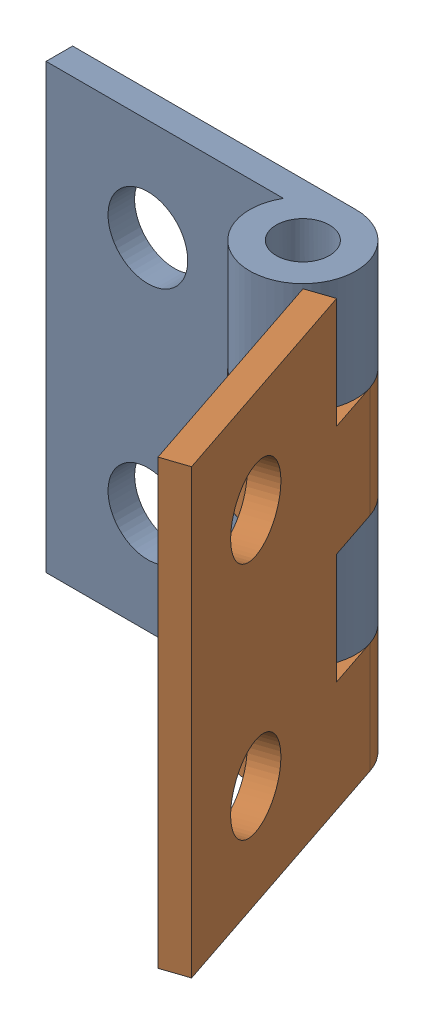
SolidWorks assembly 铰链, configuration 默认. Lengths in mm.
Overall size (23.93 25 19.92).
2 component instances, 1 part files, 2 mates.
Components (placement in the parent):
- 铰链_half-1: 铰链_half [默认] at (-3.8519 1.7615 -3) size (19 25 6)
- 铰链_half-2: 铰链_half [默认] at (11.5138 1.7615 8.0525) x (-0.318051 0 -0.948074) z (-0.948074 0 0.318051) size (19 25 6)
Mates (geometry in assembly coordinates):
- 重合1: coincident anti-aligned: plane of 铰链_half-1 through (8.6481 8.0115 3) normal (0 -1 0); plane of 铰链_half-2 through (1.8497 8.0115 -1.8901) normal (0 1 0)
- 同心1: concentric anti-aligned: circle of 铰链_half-1; circle of 铰链_half-2
